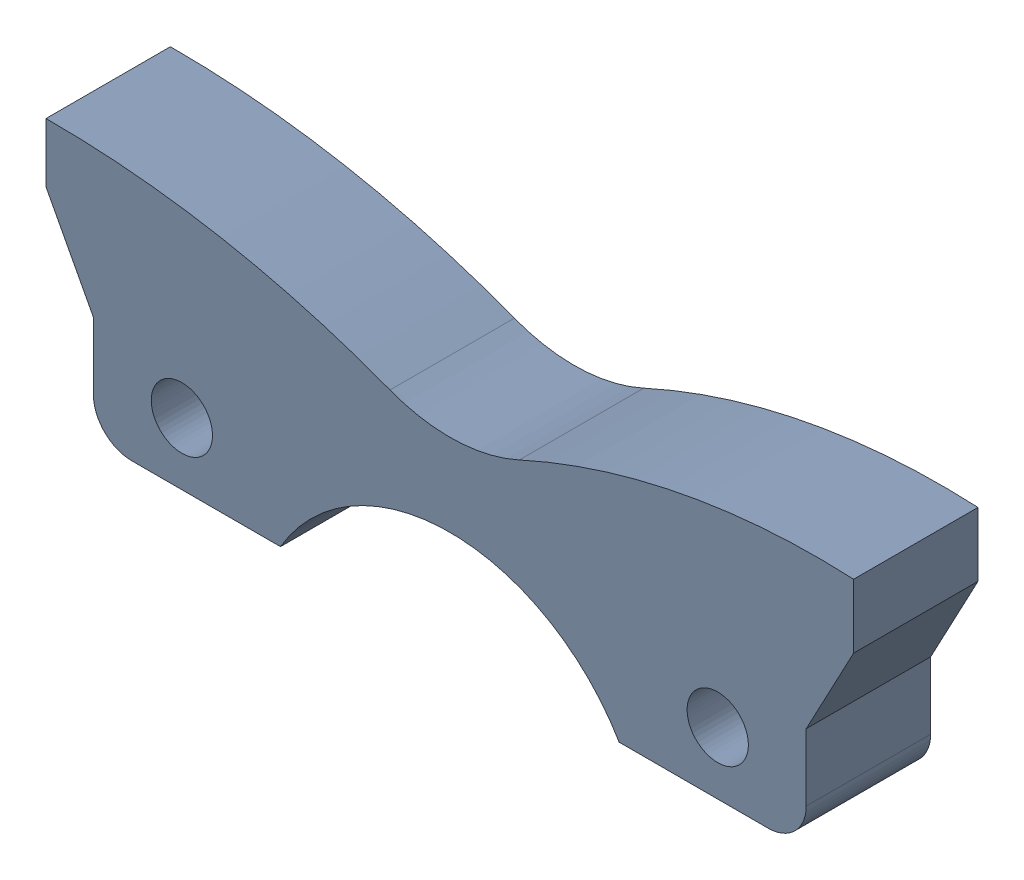
SolidWorks assembly MFG CW Cam Standin Asmbly, configuration Default. Lengths in mm.
Overall size (84.4 27.1 13).
3 component instances, 2 part files, 0 mates.
Components (placement in the parent):
- MFG CW Cam Standin-1: MFG CW Cam Standin [Default] at origin size (84.4 27.1 13)
- M6 x 1 Hex Nut-1: M6 x 1 Hex Nut [Default] at (28 205.85 53.7) x (0 -1 0) z (0 0 1) size (10 11.55 5)
- M6 x 1 Hex Nut-2: M6 x 1 Hex Nut [Default] at (-28 205.85 53.7) x (0 -1 0) z (0 0 1) size (10 11.55 5)
